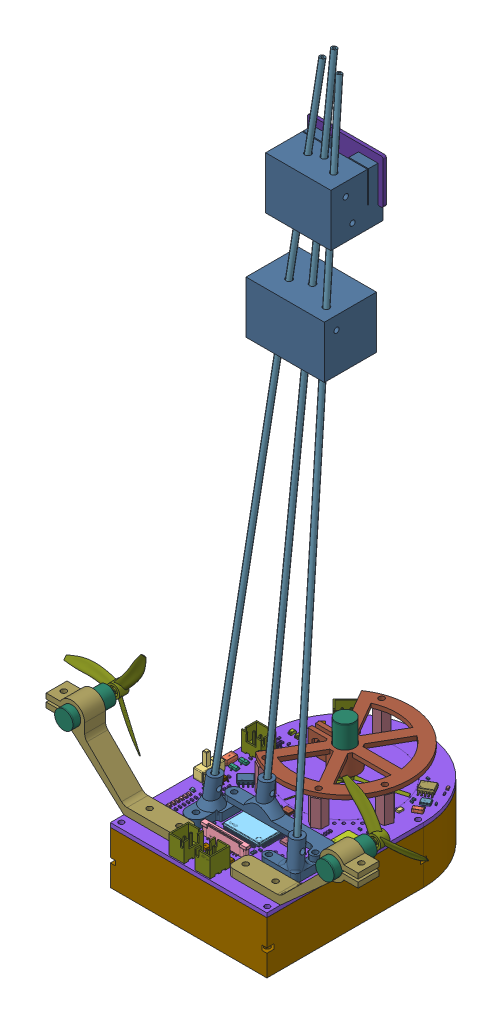
SolidWorks assembly full_assem, configuration Default. Lengths in mm.
Overall size (142.83 265.85 90).
339 component instances, 35 part files, 46 mates.
Components (placement in the parent):
- 3D_Main_v2_2024-07-05.step-1: 3D_Main_v2_2024-07-05.step [Default] at (-0.0126 0 0.0126) x (1 0 0) z (0 1 0) size (59.97 89.97 15.19)
  - a2ZF-C2.step-1: a2ZF-C2.step [Default] at (-11.43 -27.9401 1.5862) size (1 0.5 0.5)
    - C0402.step-1: C0402.step [Default] at origin size (1 0.5 0.5)
      - SOLID.step-1: SOLID.step [Default] at origin size (1 0.5 0.5)
  - a2ZF-C3.step-1: a2ZF-C3.step [Default] at (-2.286 -22.479 1.5862) x (0 -1 0) z (0 0 1) size (1 0.5 0.5)
    - C0402.step-1: C0402.step [Default] at origin size (1 0.5 0.5)
      - SOLID.step-1: SOLID.step [Default] at origin size (1 0.5 0.5)
  - a2ZF-C4.step-1: a2ZF-C4.step [Default] at (3.302 -22.479 1.5862) x (0 1 0) z (0 0 1) size (1 0.5 0.5)
    - C0402.step-1: C0402.step [Default] at origin size (1 0.5 0.5)
      - SOLID.step-1: SOLID.step [Default] at origin size (1 0.5 0.5)
  - a2ZF-C5.step-1: a2ZF-C5.step [Default] at (-4.445 -22.225 1.5862) x (0 -1 0) z (0 0 1) size (1 0.5 0.5)
    - C0402.step-1: C0402.step [Default] at origin size (1 0.5 0.5)
      - SOLID.step-1: SOLID.step [Default] at origin size (1 0.5 0.5)
  - a2ZF-C6.step-1: a2ZF-C6.step [Default] at (8.255 -40.6401 1.5862) x (-1 0 0) z (0 0 1) size (1 0.5 0.5)
    - C0402.step-1: C0402.step [Default] at origin size (1 0.5 0.5)
      - SOLID.step-1: SOLID.step [Default] at origin size (1 0.5 0.5)
  - a2ZF-C7.step-1: a2ZF-C7.step [Default] at (27.3051 -27.9401 1.5862) x (0 1 0) z (0 0 1) size (1 0.5 0.5)
    - C0402.step-1: C0402.step [Default] at origin size (1 0.5 0.5)
      - SOLID.step-1: SOLID.step [Default] at origin size (1 0.5 0.5)
  - a2ZF-C10.step-1: a2ZF-C10.step [Default] at (7.62 -43.1801 1.5862) size (1 0.5 0.5)
    - C0402.step-1: C0402.step [Default] at origin size (1 0.5 0.5)
      - SOLID.step-1: SOLID.step [Default] at origin size (1 0.5 0.5)
  - a2ZF-C9.step-1: a2ZF-C9.step [Default] at (7.62 -42.1641 1.5862) size (1 0.5 0.5)
    - C0402.step-1: C0402.step [Default] at origin size (1 0.5 0.5)
      - SOLID.step-1: SOLID.step [Default] at origin size (1 0.5 0.5)
  - a2ZF-C11.step-1: a2ZF-C11.step [Default] at (-17.78 -31.7501 1.5862) x (0 1 0) z (0 0 1) size (1 0.5 0.5)
    - C0402.step-1: C0402.step [Default] at origin size (1 0.5 0.5)
      - SOLID.step-1: SOLID.step [Default] at origin size (1 0.5 0.5)
  - a2ZF-C37.step-1: a2ZF-C37.step [Default] at (-21.59 -27.3051 1.5862) x (-1 0 0) z (0 0 1) size (1 0.5 0.5)
    - C0402.step-1: C0402.step [Default] at origin size (1 0.5 0.5)
      - SOLID.step-1: SOLID.step [Default] at origin size (1 0.5 0.5)
  - a2ZF-C12.step-1: a2ZF-C12.step [Default] at (20.32 -14.605 1.5862) x (-1 0 0) z (0 0 1) size (1 0.5 0.5)
    - C0402.step-1: C0402.step [Default] at origin size (1 0.5 0.5)
      - SOLID.step-1: SOLID.step [Default] at origin size (1 0.5 0.5)
  - a2ZF-C14.step-1: a2ZF-C14.step [Default] at (14.605 -25.4001 1.5862) size (1 0.5 0.5)
    - C0402.step-1: C0402.step [Default] at origin size (1 0.5 0.5)
      - SOLID.step-1: SOLID.step [Default] at origin size (1 0.5 0.5)
  - a2ZF-C15.step-1: a2ZF-C15.step [Default] at (24.892 -29.2101 1.5862) x (0 1 0) z (0 0 1) size (1 0.5 0.5)
    - C0402.step-1: C0402.step [Default] at origin size (1 0.5 0.5)
      - SOLID.step-1: SOLID.step [Default] at origin size (1 0.5 0.5)
  - a2ZF-C17.step-1: a2ZF-C17.step [Default] at (19.304 -29.2101 1.5862) x (0 -1 0) z (0 0 1) size (1 0.5 0.5)
    - C0402.step-1: C0402.step [Default] at origin size (1 0.5 0.5)
      - SOLID.step-1: SOLID.step [Default] at origin size (1 0.5 0.5)
  - a2ZF-C19.step-1: a2ZF-C19.step [Default] at (27.3051 -16.51 1.5862) x (0 -1 0) z (0 0 1) size (1 0.5 0.5)
    - C0402.step-1: C0402.step [Default] at origin size (1 0.5 0.5)
      - SOLID.step-1: SOLID.step [Default] at origin size (1 0.5 0.5)
  - a2ZF-C21.step-1: a2ZF-C21.step [Default] at (21.082 4.445 1.5862) x (-1 0 0) z (0 0 1) size (1 0.5 0.5)
    - C0402.step-1: C0402.step [Default] at origin size (1 0.5 0.5)
      - SOLID.step-1: SOLID.step [Default] at origin size (1 0.5 0.5)
  - a2ZF-C22.step-1: a2ZF-C22.step [Default] at (20.701 5.715 1.5862) size (1 0.5 0.5)
    - C0402.step-1: C0402.step [Default] at origin size (1 0.5 0.5)
      - SOLID.step-1: SOLID.step [Default] at origin size (1 0.5 0.5)
  - a2ZF-C23.step-1: a2ZF-C23.step [Default] at (16.51 15.24 1.5862) x (-1 0 0) z (0 0 1) size (1 0.5 0.5)
    - C0402.step-1: C0402.step [Default] at origin size (1 0.5 0.5)
      - SOLID.step-1: SOLID.step [Default] at origin size (1 0.5 0.5)
  - a2ZF-C24.step-1: a2ZF-C24.step [Default] at (-5.715 -50.8001 1.5862) x (-1 0 0) z (0 0 1) size (1 0.5 0.5)
    - C0402.step-1: C0402.step [Default] at origin size (1 0.5 0.5)
      - SOLID.step-1: SOLID.step [Default] at origin size (1 0.5 0.5)
  - a2ZF-C25.step-1: a2ZF-C25.step [Default] at (-5.715 -49.5301 1.5862) x (-1 0 0) z (0 0 1) size (1 0.5 0.5)
    - C0402.step-1: C0402.step [Default] at origin size (1 0.5 0.5)
      - SOLID.step-1: SOLID.step [Default] at origin size (1 0.5 0.5)
  - a2ZF-C26.step-1: a2ZF-C26.step [Default] at (25.2731 4.699 1.5862) x (0.866025 0.5 0) z (0 0 1) size (1 0.5 0.5)
    - C0402.step-1: C0402.step [Default] at origin size (1 0.5 0.5)
      - SOLID.step-1: SOLID.step [Default] at origin size (1 0.5 0.5)
  - a2ZF-C27.step-1: a2ZF-C27.step [Default] at (26.5431 8.382 1.5862) x (-0.5 0.866025 0) z (0 0 1) size (1 0.5 0.5)
    - C0402.step-1: C0402.step [Default] at origin size (1 0.5 0.5)
      - SOLID.step-1: SOLID.step [Default] at origin size (1 0.5 0.5)
  - a2ZF-C28.step-1: a2ZF-C28.step [Default] at (3.175 -50.8001 1.5862) x (-1 0 0) z (0 0 1) size (1 0.5 0.5)
    - C0402.step-1: C0402.step [Default] at origin size (1 0.5 0.5)
      - SOLID.step-1: SOLID.step [Default] at origin size (1 0.5 0.5)
  - a2ZF-C29.step-1: a2ZF-C29.step [Default] at (3.175 -49.5301 1.5862) x (-1 0 0) z (0 0 1) size (1 0.5 0.5)
    - C0402.step-1: C0402.step [Default] at origin size (1 0.5 0.5)
      - SOLID.step-1: SOLID.step [Default] at origin size (1 0.5 0.5)
  - a2ZF-C30.step-1: a2ZF-C30.step [Default] at (-19.05 11.43 1.5862) x (0.707107 -0.707107 0) z (0 0 1) size (1 0.5 0.5)
    - C0402.step-1: C0402.step [Default] at origin size (1 0.5 0.5)
      - SOLID.step-1: SOLID.step [Default] at origin size (1 0.5 0.5)
  - a2ZF-C31.step-1: a2ZF-C31.step [Default] at (-20.32 10.16 1.5862) x (0.707107 -0.707107 0) z (0 0 1) size (1 0.5 0.5)
    - C0402.step-1: C0402.step [Default] at origin size (1 0.5 0.5)
      - SOLID.step-1: SOLID.step [Default] at origin size (1 0.5 0.5)
  - a2ZF-C32.step-1: a2ZF-C32.step [Default] at (-13.462 -18.034 1.5862) x (0.707107 0.707107 0) z (0 0 1) size (1 0.5 0.5)
    - C0402.step-1: C0402.step [Default] at origin size (1 0.5 0.5)
      - SOLID.step-1: SOLID.step [Default] at origin size (1 0.5 0.5)
  - a2ZF-C33.step-1: a2ZF-C33.step [Default] at (10.16 -26.6701 1.5862) x (0 -1 0) z (0 0 1) size (1 0.5 0.5)
    - C0402.step-1: C0402.step [Default] at origin size (1 0.5 0.5)
      - SOLID.step-1: SOLID.step [Default] at origin size (1 0.5 0.5)
  - a2ZF-C34.step-1: a2ZF-C34.step [Default] at (-15.24 -26.6701 1.5862) x (-1 0 0) z (0 0 1) size (1 0.5 0.5)
    - C0402.step-1: C0402.step [Default] at origin size (1 0.5 0.5)
      - SOLID.step-1: SOLID.step [Default] at origin size (1 0.5 0.5)
  - a2ZF-C35.step-1: a2ZF-C35.step [Default] at (-5.715 -22.225 1.5862) x (0 1 0) z (0 0 1) size (1 0.5 0.5)
    - C0402.step-1: C0402.step [Default] at origin size (1 0.5 0.5)
      - SOLID.step-1: SOLID.step [Default] at origin size (1 0.5 0.5)
  - a2ZF-C36.step-1: a2ZF-C36.step [Default] at (-18.415 -29.2101 1.5862) x (-1 0 0) z (0 0 1) size (1 0.5 0.5)
    - C0402.step-1: C0402.step [Default] at origin size (1 0.5 0.5)
      - SOLID.step-1: SOLID.step [Default] at origin size (1 0.5 0.5)
  - a2ZF-C8.step-1: a2ZF-C8.step [Default] at (5.08 -22.86 1.5862) x (0 1 0) z (0 0 1) size (1 0.5 0.5)
    - C0402.step-1: C0402.step [Default] at origin size (1 0.5 0.5)
      - SOLID.step-1: SOLID.step [Default] at origin size (1 0.5 0.5)
  - a2ZF-C38.step-1: a2ZF-C38.step [Default] at (-9.525 -43.1801 1.5862) x (0 1 0) z (0 0 1) size (1 0.5 0.5)
    - C0402.step-1: C0402.step [Default] at origin size (1 0.5 0.5)
      - SOLID.step-1: SOLID.step [Default] at origin size (1 0.5 0.5)
  - a2ZF-C1.step-1: a2ZF-C1.step [Default] at (-9.525 -40.6401 1.5862) x (0 1 0) z (0 0 1) size (1 0.5 0.5)
    - C0402.step-1: C0402.step [Default] at origin size (1 0.5 0.5)
      - SOLID.step-1: SOLID.step [Default] at origin size (1 0.5 0.5)
  - a2ZF-C20.step-1: a2ZF-C20.step [Default] at (25.4001 2.54 1.5862) x (-0.866025 -0.5 0) z (0 0 1) size (3.2 1.6 1.3)
    - C1206.step-1: C1206.step [Default] at origin size (3.2 1.6 1.3)
      - SOLID-0.step-1: SOLID-0.step [Default] at origin size (3.2 1.6 1.3)
  - a2ZF-L1.step-1: a2ZF-L1.step [Default] at (21.59 -0.635 1.5862) x (0 1 0) z (0 0 1) size (2 1.3 0.61)
    - L0805.step-1: L0805.step [Default] at origin size (2 1.3 0.61)
      - COMPOUND.step-1: COMPOUND.step [Default] at origin size (2 1.3 0.61)
  - a2ZF-LED8.step-1: a2ZF-LED8.step [Default] at (24.257 -11.43 1.5862) x (0 -1 0) z (0 0 1) size (1.62 0.82 0.56)
    - LED0603-RD-YELLOW.step-1: LED0603-RD-YELLOW.step [Default] at origin size (1.62 0.82 0.56)
      - COMPOUND-1.step-1: COMPOUND-1.step [Default] at origin size (1.62 0.82 0.56)
  - a2ZF-LED2.step-1: a2ZF-LED2.step [Default] at (-24.13 -35.5601 1.5862) size (1.62 0.82 0.56)
    - LED0603-RD-YELLOW.step-1: LED0603-RD-YELLOW.step [Default] at origin size (1.62 0.82 0.56)
      - COMPOUND-1.step-1: COMPOUND-1.step [Default] at origin size (1.62 0.82 0.56)
  - a2ZF-LED3.step-1: a2ZF-LED3.step [Default] at (-24.13 -37.0841 1.5862) size (1.62 0.82 0.56)
    - LED0603-RD-YELLOW.step-1: LED0603-RD-YELLOW.step [Default] at origin size (1.62 0.82 0.56)
      - COMPOUND-1.step-1: COMPOUND-1.step [Default] at origin size (1.62 0.82 0.56)
  - a2ZF-LED4.step-1: a2ZF-LED4.step [Default] at (-24.13 -38.6081 1.5862) size (1.62 0.82 0.56)
    - LED0603-RD-YELLOW.step-1: LED0603-RD-YELLOW.step [Default] at origin size (1.62 0.82 0.56)
      - COMPOUND-1.step-1: COMPOUND-1.step [Default] at origin size (1.62 0.82 0.56)
  - a2ZF-LED5.step-1: a2ZF-LED5.step [Default] at (-24.13 -40.1321 1.5862) size (1.62 0.82 0.56)
    - LED0603-RD-YELLOW.step-1: LED0603-RD-YELLOW.step [Default] at origin size (1.62 0.82 0.56)
      - COMPOUND-1.step-1: COMPOUND-1.step [Default] at origin size (1.62 0.82 0.56)
  - a2ZF-LED6.step-1: a2ZF-LED6.step [Default] at (-24.13 -41.6561 1.5862) size (1.62 0.82 0.56)
    - LED0603-RD-YELLOW.step-1: LED0603-RD-YELLOW.step [Default] at origin size (1.62 0.82 0.56)
      - COMPOUND-1.step-1: COMPOUND-1.step [Default] at origin size (1.62 0.82 0.56)
  - a2ZF-LED7.step-1: a2ZF-LED7.step [Default] at (-24.13 -43.1801 1.5862) size (1.62 0.82 0.56)
    - LED0603-RD-YELLOW.step-1: LED0603-RD-YELLOW.step [Default] at origin size (1.62 0.82 0.56)
      - COMPOUND-1.step-1: COMPOUND-1.step [Default] at origin size (1.62 0.82 0.56)
  - a2ZF-LED10.step-1: a2ZF-LED10.step [Default] at (23.495 15.875 1.5862) x (0.5 -0.866025 0) z (0 0 1) size (1.62 0.82 0.56)
    - LED0603-RD-YELLOW.step-1: LED0603-RD-YELLOW.step [Default] at origin size (1.62 0.82 0.56)
      - COMPOUND-1.step-1: COMPOUND-1.step [Default] at origin size (1.62 0.82 0.56)
  - a2ZF-LED9.step-1: a2ZF-LED9.step [Default] at (22.733 -11.43 1.5862) x (0 -1 0) z (0 0 1) size (1.62 0.82 0.56)
    - LED0603-RD-YELLOW.step-1: LED0603-RD-YELLOW.step [Default] at origin size (1.62 0.82 0.56)
      - COMPOUND-1.step-1: COMPOUND-1.step [Default] at origin size (1.62 0.82 0.56)
  - a2ZF-LED1.step-1: a2ZF-LED1.step [Default] at (-24.765 -33.6551 1.5862) size (1.62 0.81 0.81)
    - LED0603-R-RD_WHITE.step-1: LED0603-R-RD_WHITE.step [Default] at origin size (1.62 0.81 0.81)
      - COMPOUND-2.step-1: COMPOUND-2.step [Default] at origin size (1.62 0.81 0.81)
  - a2ZF-L2.step-1: a2ZF-L2.step [Default] at (-22.225 -29.8451 1.5862) size (3 3 1.52)
    - IND-SMD_L3.0-W3.0_FNR30XXS.step-1: IND-SMD_L3.0-W3.0_FNR30XXS.step [Default] at origin size (3 3 1.52)
      - SOLID-3.step-1: SOLID-3.step [Default] at origin size (3 3 1.52)
  - a2ZF-LED12.step-1: a2ZF-LED12.step [Default] at (-22.225 4.445 1.5862) x (0 1 0) z (0 0 1) size (2.02 1.26 1.01)
    - LED0805-R-RD.step-1: LED0805-R-RD.step [Default] at origin size (2.02 1.26 1.01)
      - COMPOUND-4.step-1: COMPOUND-4.step [Default] at origin size (2.02 1.26 1.01)
  - a2ZF-LED11.step-1: a2ZF-LED11.step [Default] at (-24.765 4.445 1.5862) x (0 1 0) z (0 0 1) size (2.02 1.26 1.01)
    - LED0805-R-RD.step-1: LED0805-R-RD.step [Default] at origin size (2.02 1.26 1.01)
      - COMPOUND-4.step-1: COMPOUND-4.step [Default] at origin size (2.02 1.26 1.01)
  - a2ZF-R2.step-1: a2ZF-R2.step [Default] at (-3.302 -22.479 1.5862) x (0 -1 0) z (0 0 1) size (1 0.5 0.5)
    - R0402.step-1: R0402.step [Default] at origin size (1 0.5 0.5)
      - SOLID-5.step-1: SOLID-5.step [Default] at origin size (1 0.5 0.5)
  - a2ZF-R3.step-1: a2ZF-R3.step [Default] at (-7.62 -43.1801 1.5862) size (1 0.5 0.5)
    - R0402.step-1: R0402.step [Default] at origin size (1 0.5 0.5)
      - SOLID-5.step-1: SOLID-5.step [Default] at origin size (1 0.5 0.5)
  - a2ZF-R4.step-1: a2ZF-R4.step [Default] at (-7.62 -48.2601 1.5862) size (1 0.5 0.5)
    - R0402.step-1: R0402.step [Default] at origin size (1 0.5 0.5)
      - SOLID-5.step-1: SOLID-5.step [Default] at origin size (1 0.5 0.5)
  - a2ZF-R5.step-1: a2ZF-R5.step [Default] at (-21.59 -33.6551 1.5862) size (1 0.5 0.5)
    - R0402.step-1: R0402.step [Default] at origin size (1 0.5 0.5)
      - SOLID-5.step-1: SOLID-5.step [Default] at origin size (1 0.5 0.5)
  - a2ZF-R13.step-1: a2ZF-R13.step [Default] at (26.0351 -29.2101 1.5862) x (0 1 0) z (0 0 1) size (1 0.5 0.5)
    - R0402.step-1: R0402.step [Default] at origin size (1 0.5 0.5)
      - SOLID-5.step-1: SOLID-5.step [Default] at origin size (1 0.5 0.5)
  - a2ZF-R12.step-1: a2ZF-R12.step [Default] at (15.24 -24.13 1.5862) x (-1 0 0) z (0 0 1) size (1 0.5 0.5)
    - R0402.step-1: R0402.step [Default] at origin size (1 0.5 0.5)
      - SOLID-5.step-1: SOLID-5.step [Default] at origin size (1 0.5 0.5)
  - a2ZF-R6.step-1: a2ZF-R6.step [Default] at (-21.59 -35.5601 1.5862) size (1 0.5 0.5)
    - R0402.step-1: R0402.step [Default] at origin size (1 0.5 0.5)
      - SOLID-5.step-1: SOLID-5.step [Default] at origin size (1 0.5 0.5)
  - a2ZF-R7.step-1: a2ZF-R7.step [Default] at (-21.59 -37.0841 1.5862) size (1 0.5 0.5)
    - R0402.step-1: R0402.step [Default] at origin size (1 0.5 0.5)
      - SOLID-5.step-1: SOLID-5.step [Default] at origin size (1 0.5 0.5)
  - a2ZF-R8.step-1: a2ZF-R8.step [Default] at (-21.59 -38.6081 1.5862) size (1 0.5 0.5)
    - R0402.step-1: R0402.step [Default] at origin size (1 0.5 0.5)
      - SOLID-5.step-1: SOLID-5.step [Default] at origin size (1 0.5 0.5)
  - a2ZF-R9.step-1: a2ZF-R9.step [Default] at (-21.59 -40.1321 1.5862) size (1 0.5 0.5)
    - R0402.step-1: R0402.step [Default] at origin size (1 0.5 0.5)
      - SOLID-5.step-1: SOLID-5.step [Default] at origin size (1 0.5 0.5)
  - a2ZF-R10.step-1: a2ZF-R10.step [Default] at (-21.59 -41.6561 1.5862) size (1 0.5 0.5)
    - R0402.step-1: R0402.step [Default] at origin size (1 0.5 0.5)
      - SOLID-5.step-1: SOLID-5.step [Default] at origin size (1 0.5 0.5)
  - a2ZF-R11.step-1: a2ZF-R11.step [Default] at (-21.59 -43.1801 1.5862) size (1 0.5 0.5)
    - R0402.step-1: R0402.step [Default] at origin size (1 0.5 0.5)
      - SOLID-5.step-1: SOLID-5.step [Default] at origin size (1 0.5 0.5)
  - a2ZF-R14.step-1: a2ZF-R14.step [Default] at (24.13 -13.97 1.5862) x (0 -1 0) z (0 0 1) size (1 0.5 0.5)
    - R0402.step-1: R0402.step [Default] at origin size (1 0.5 0.5)
      - SOLID-5.step-1: SOLID-5.step [Default] at origin size (1 0.5 0.5)
  - a2ZF-R15.step-1: a2ZF-R15.step [Default] at (22.86 -13.97 1.5862) x (0 -1 0) z (0 0 1) size (1 0.5 0.5)
    - R0402.step-1: R0402.step [Default] at origin size (1 0.5 0.5)
      - SOLID-5.step-1: SOLID-5.step [Default] at origin size (1 0.5 0.5)
  - a2ZF-R16.step-1: a2ZF-R16.step [Default] at (28.5751 -13.97 1.5862) x (0 1 0) z (0 0 1) size (1 0.5 0.5)
    - R0402.step-1: R0402.step [Default] at origin size (1 0.5 0.5)
      - SOLID-5.step-1: SOLID-5.step [Default] at origin size (1 0.5 0.5)
  - a2ZF-R17.step-1: a2ZF-R17.step [Default] at (27.3051 -13.97 1.5862) x (0 1 0) z (0 0 1) size (1 0.5 0.5)
    - R0402.step-1: R0402.step [Default] at origin size (1 0.5 0.5)
      - SOLID-5.step-1: SOLID-5.step [Default] at origin size (1 0.5 0.5)
  - a2ZF-R18.step-1: a2ZF-R18.step [Default] at (28.5751 -16.637 1.5862) x (0 1 0) z (0 0 1) size (1 0.5 0.5)
    - R0402.step-1: R0402.step [Default] at origin size (1 0.5 0.5)
      - SOLID-5.step-1: SOLID-5.step [Default] at origin size (1 0.5 0.5)
  - a2ZF-R19.step-1: a2ZF-R19.step [Default] at (15.24 -22.86 1.5862) x (-1 0 0) z (0 0 1) size (1 0.5 0.5)
    - R0402.step-1: R0402.step [Default] at origin size (1 0.5 0.5)
      - SOLID-5.step-1: SOLID-5.step [Default] at origin size (1 0.5 0.5)
  - a2ZF-R20.step-1: a2ZF-R20.step [Default] at (15.24 -21.844 1.5862) x (-1 0 0) z (0 0 1) size (1 0.5 0.5)
    - R0402.step-1: R0402.step [Default] at origin size (1 0.5 0.5)
      - SOLID-5.step-1: SOLID-5.step [Default] at origin size (1 0.5 0.5)
  - a2ZF-R21.step-1: a2ZF-R21.step [Default] at (15.24 -20.828 1.5862) x (-1 0 0) z (0 0 1) size (1 0.5 0.5)
    - R0402.step-1: R0402.step [Default] at origin size (1 0.5 0.5)
      - SOLID-5.step-1: SOLID-5.step [Default] at origin size (1 0.5 0.5)
  - a2ZF-R23.step-1: a2ZF-R23.step [Default] at (-19.05 -27.3051 1.5862) x (0 -1 0) z (0 0 1) size (1 0.5 0.5)
    - R0402.step-1: R0402.step [Default] at origin size (1 0.5 0.5)
      - SOLID-5.step-1: SOLID-5.step [Default] at origin size (1 0.5 0.5)
  - a2ZF-R24.step-1: a2ZF-R24.step [Default] at (-6.985 -20.32 1.5862) x (0 1 0) z (0 0 1) size (1 0.5 0.5)
    - R0402.step-1: R0402.step [Default] at origin size (1 0.5 0.5)
      - SOLID-5.step-1: SOLID-5.step [Default] at origin size (1 0.5 0.5)
  - a2ZF-R25.step-1: a2ZF-R25.step [Default] at (-19.05 -25.4001 1.5862) x (0 -1 0) z (0 0 1) size (1 0.5 0.5)
    - R0402.step-1: R0402.step [Default] at origin size (1 0.5 0.5)
      - SOLID-5.step-1: SOLID-5.step [Default] at origin size (1 0.5 0.5)
  - a2ZF-R26.step-1: a2ZF-R26.step [Default] at (-6.985 -22.225 1.5862) x (0 1 0) z (0 0 1) size (1 0.5 0.5)
    - R0402.step-1: R0402.step [Default] at origin size (1 0.5 0.5)
      - SOLID-5.step-1: SOLID-5.step [Default] at origin size (1 0.5 0.5)
  - a2ZF-R27.step-1: a2ZF-R27.step [Default] at (-22.225 -22.225 1.5862) size (1 0.5 0.5)
    - R0402.step-1: R0402.step [Default] at origin size (1 0.5 0.5)
      - SOLID-5.step-1: SOLID-5.step [Default] at origin size (1 0.5 0.5)
  - a2ZF-R28.step-1: a2ZF-R28.step [Default] at (-25.4001 0 1.5862) x (0 1 0) z (0 0 1) size (1 0.5 0.5)
    - R0402.step-1: R0402.step [Default] at origin size (1 0.5 0.5)
      - SOLID-5.step-1: SOLID-5.step [Default] at origin size (1 0.5 0.5)
  - a2ZF-R29.step-1: a2ZF-R29.step [Default] at (-23.495 -0.635 1.5862) x (-1 0 0) z (0 0 1) size (1 0.5 0.5)
    - R0402.step-1: R0402.step [Default] at origin size (1 0.5 0.5)
      - SOLID-5.step-1: SOLID-5.step [Default] at origin size (1 0.5 0.5)
  - a2ZF-R31.step-1: a2ZF-R31.step [Default] at (-21.59 0 1.5862) x (0 1 0) z (0 0 1) size (1 0.5 0.5)
    - R0402.step-1: R0402.step [Default] at origin size (1 0.5 0.5)
      - SOLID-5.step-1: SOLID-5.step [Default] at origin size (1 0.5 0.5)
  - a2ZF-R22.step-1: a2ZF-R22.step [Default] at (24.765 13.335 1.5862) x (0.5 -0.866025 0) z (0 0 1) size (1 0.5 0.5)
    - R0402.step-1: R0402.step [Default] at origin size (1 0.5 0.5)
      - SOLID-5.step-1: SOLID-5.step [Default] at origin size (1 0.5 0.5)
  - a2ZF-R30.step-1: a2ZF-R30.step [Default] at (-24.13 -12.065 1.5862) x (-1 0 0) z (0 0 1) size (1 0.5 0.5)
    - R0402.step-1: R0402.step [Default] at origin size (1 0.5 0.5)
      - SOLID-5.step-1: SOLID-5.step [Default] at origin size (1 0.5 0.5)
  - a2ZF-R1.step-1: a2ZF-R1.step [Default] at (10.16 -29.2101 1.5862) size (1 0.5 0.5)
    - R0402.step-1: R0402.step [Default] at origin size (1 0.5 0.5)
      - SOLID-5.step-1: SOLID-5.step [Default] at origin size (1 0.5 0.5)
  - a2ZF-U5.step-1: a2ZF-U5.step [Default] at (5.715 -50.1651 1.5862) x (0 1 0) z (0 0 1) size (2.02 2 0.81)
    - WSON-8_L2.0-W2.0-P0.50-TL-EP.step-1: WSON-8_L2.0-W2.0-P0.50-TL-EP.step [Default] at origin size (2.02 2 0.81)
      - COMPOUND-6.step-1: COMPOUND-6.step [Default] at origin size (2.02 2 0.81)
  - a2ZF-U6.step-1: a2ZF-U6.step [Default] at (-21.59 12.7 1.5862) x (-0.707107 -0.707107 0) z (0 0 1) size (2.02 2 0.81)
    - WSON-8_L2.0-W2.0-P0.50-TL-EP.step-1: WSON-8_L2.0-W2.0-P0.50-TL-EP.step [Default] at origin size (2.02 2 0.81)
      - COMPOUND-6.step-1: COMPOUND-6.step [Default] at origin size (2.02 2 0.81)
  - a2ZF-U4.step-1: a2ZF-U4.step [Default] at (-3.175 -50.1651 1.5862) x (0 1 0) z (0 0 1) size (2.02 2 0.81)
    - WSON-8_L2.0-W2.0-P0.50-TL-EP.step-1: WSON-8_L2.0-W2.0-P0.50-TL-EP.step [Default] at origin size (2.02 2 0.81)
      - COMPOUND-6.step-1: COMPOUND-6.step [Default] at origin size (2.02 2 0.81)
  - a2ZF-U7.step-1: a2ZF-U7.step [Default] at (-17.78 -20.32 1.5862) x (-0.707107 -0.707107 0) z (0 0 1) size (4.9 6 1.5)
    - SOP-8_L4.9-W3.9-P1.27-LS6.0-BL.step-1: SOP-8_L4.9-W3.9-P1.27-LS6.0-BL.step [Default] at origin size (4.9 6 1.5)
      - COMPOUND-7.step-1: COMPOUND-7.step [Default] at origin size (4.9 6 1.5)
  - a2ZF-X2.step-1: a2ZF-X2.step [Default] at (22.098 -29.2101 1.5862) size (3.2 2.5 0.81)
    - OSC-SMD_4P-L3.2-W2.5-BL.step-1: OSC-SMD_4P-L3.2-W2.5-BL.step [Default] at origin size (3.2 2.5 0.81)
      - SOLID-8.step-1: SOLID-8.step [Default] at origin size (3.2 2.5 0.81)
  - a2ZF-X1.step-1: a2ZF-X1.step [Default] at (0.508 -22.479 1.5862) x (-1 0 0) z (0 0 1) size (3.2 2.5 0.81)
    - OSC-SMD_4P-L3.2-W2.5-BL.step-1: OSC-SMD_4P-L3.2-W2.5-BL.step [Default] at origin size (3.2 2.5 0.81)
      - SOLID-8.step-1: SOLID-8.step [Default] at origin size (3.2 2.5 0.81)
  - a2ZF-U3.step-1: a2ZF-U3.step [Default] at (20.193 11.43 1.5862) x (0.866025 0.5 0) z (0 0 1) size (5 6 1.8)
    - SSOP-10_L5.0-W3.9-P1.00-LS6.0-BL-EP.step-1: SSOP-10_L5.0-W3.9-P1.00-LS6.0-BL-EP.step [Default] at origin size (5 6 1.8)
      - COMPOUND-9.step-1: COMPOUND-9.step [Default] at origin size (5 6 1.8)
  - a2ZF-U8.step-1: a2ZF-U8.step [Default] at (10.795 -33.0201 1.5862) size (3 2.5 0.92)
    - LGA-14_L3.0-W2.5-P0.50-TL.step-1: LGA-14_L3.0-W2.5-P0.50-TL.step [Default] at origin size (3 2.5 0.92)
      - COMPOUND-10.step-1: COMPOUND-10.step [Default] at origin size (3 2.5 0.92)
  - a2ZF-X3.step-1: a2ZF-X3.step [Default] at (24.003 6.985 1.5862) x (0.866025 0.5 0) z (0 0 1) size (3.2 2.5 0.81)
    - CRYSTAL-SMD_4P-L3.2-W2.5-BL.step-1: CRYSTAL-SMD_4P-L3.2-W2.5-BL.step [Default] at origin size (3.2 2.5 0.81)
      - SOLID-11.step-1: SOLID-11.step [Default] at origin size (3.2 2.5 0.81)
  - a2ZF-CN2.step-1: a2ZF-CN2.step [Default] at (17.78 -31.7501 0) x (0 1 0) z (0 0 -1) size (8 3.2 6.9)
    - CONN-TH_5P-P1.25_HCTL_HC-1.25-5A.step-1: CONN-TH_5P-P1.25_HCTL_HC-1.25-5A.step [Default] at origin size (8 3.2 6.9)
      - COMPOUND-12.step-1: COMPOUND-12.step [Default] at origin size (8 3.2 6.9)
  - a2ZF-CN6.step-1: a2ZF-CN6.step [Default] at (-17.145 -14.605 1.5862) x (-0.707107 0.707107 0) z (0 0 1) size (8 3.2 6.9)
    - CONN-TH_5P-P1.25_HCTL_HC-1.25-5A.step-1: CONN-TH_5P-P1.25_HCTL_HC-1.25-5A.step [Default] at origin size (8 3.2 6.9)
      - COMPOUND-12.step-1: COMPOUND-12.step [Default] at origin size (8 3.2 6.9)
  - a2ZF-CN1.step-1: a2ZF-CN1.step [Default] at (13.97 -31.7501 0) x (0 1 0) z (0 0 -1) size (8 3.2 6.9)
    - CONN-TH_5P-P1.25_HCTL_HC-1.25-5A.step-1: CONN-TH_5P-P1.25_HCTL_HC-1.25-5A.step [Default] at origin size (8 3.2 6.9)
      - COMPOUND-12.step-1: COMPOUND-12.step [Default] at origin size (8 3.2 6.9)
  - a2ZF-CN4.step-1: a2ZF-CN4.step [Default] at (4.445 -55.8801 1.5862) x (0 1 0) z (0 0 1) size (7.5 5.9 10.6)
    - CONN-TH_2P-P2.50_HX25003-2A.step-1: CONN-TH_2P-P2.50_HX25003-2A.step [Default] at origin size (7.5 5.9 10.6)
      - COMPOUND-13.step-1: COMPOUND-13.step [Default] at origin size (7.5 5.9 10.6)
  - a2ZF-CN5.step-1: a2ZF-CN5.step [Default] at (-15.875 16.51 1.5862) x (-0.707107 -0.707107 0) z (0 0 1) size (7.5 5.9 10.6)
    - CONN-TH_2P-P2.50_HX25003-2A.step-1: CONN-TH_2P-P2.50_HX25003-2A.step [Default] at origin size (7.5 5.9 10.6)
      - COMPOUND-13.step-1: COMPOUND-13.step [Default] at origin size (7.5 5.9 10.6)
  - a2ZF-CN7.step-1: a2ZF-CN7.step [Default] at (-24.765 -8.89 1.5862) x (-1 0 0) z (0 0 1) size (7.5 5.9 10.6)
    - CONN-TH_2P-P2.50_HX25003-2A.step-1: CONN-TH_2P-P2.50_HX25003-2A.step [Default] at origin size (7.5 5.9 10.6)
      - COMPOUND-13.step-1: COMPOUND-13.step [Default] at origin size (7.5 5.9 10.6)
  - a2ZF-CN3.step-1: a2ZF-CN3.step [Default] at (-4.445 -55.8801 1.5862) x (0 -1 0) z (0 0 1) size (7.5 5.9 10.6)
    - CONN-TH_2P-P2.50_HX25003-2A.step-1: CONN-TH_2P-P2.50_HX25003-2A.step [Default] at origin size (7.5 5.9 10.6)
      - COMPOUND-13.step-1: COMPOUND-13.step [Default] at origin size (7.5 5.9 10.6)
  - a2ZF-U11.step-1: a2ZF-U11.step [Default] at (-23.495 -3.175 1.5862) x (-1 0 0) z (0 0 1) size (2.81 2.9 1.65)
    - SOT-23-6_L2.9-W1.6-P0.95-LS2.8-BR.step-1: SOT-23-6_L2.9-W1.6-P0.95-LS2.8-BR.step [Default] at origin size (2.81 2.9 1.65)
      - COMPOUND-14.step-1: COMPOUND-14.step [Default] at origin size (2.81 2.9 1.65)
  - a2ZF-U10.step-1: a2ZF-U10.step [Default] at (-22.225 -24.765 1.5862) x (-1 0 0) z (0 0 1) size (2.89 2.78 1.2)
    - SOT-23-5_L3.0-W1.7-P0.95-LS2.8-BR.step-1: SOT-23-5_L3.0-W1.7-P0.95-LS2.8-BR.step [Default] at origin size (2.89 2.78 1.2)
      - COMPOUND-15.step-1: COMPOUND-15.step [Default] at origin size (2.89 2.78 1.2)
  - a2ZF-U9.step-1: a2ZF-U9.step [Default] at (-15.24 -29.2101 1.5862) size (2.9 3.01 1.25)
    - SOT-23-5_L3.0-W1.7-P0.95-LS2.8-BL.step-1: SOT-23-5_L3.0-W1.7-P0.95-LS2.8-BL.step [Default] at origin size (2.9 3.01 1.25)
      - COMPOUND-16.step-1: COMPOUND-16.step [Default] at origin size (2.9 3.01 1.25)
  - a2ZF-D1.step-1: a2ZF-D1.step [Default] at (-27.3051 -17.145 1.5862) x (0 -1 0) z (0 0 1) size (4.7 2.6 2.1)
    - SMA_L4.3-W2.6-LS5.2-RD.step-1: SMA_L4.3-W2.6-LS5.2-RD.step [Default] at origin size (4.7 2.6 2.1)
      - COMPOUND-17.step-1: COMPOUND-17.step [Default] at origin size (4.7 2.6 2.1)
  - a2ZF-SW1.step-1: a2ZF-SW1.step [Default] at (-26.6701 -25.4001 1.5862) x (0 1 0) z (0 0 1) size (8.71 3.71 13.3)
    - SW-TH_KH-SS12D01-G3-5.0.step-1: SW-TH_KH-SS12D01-G3-5.0.step [Default] at origin size (8.71 3.71 13.3)
      - COMPOUND-18.step-1: COMPOUND-18.step [Default] at origin size (8.71 3.71 13.3)
  - a2ZF-FPC2.step-1: a2ZF-FPC2.step [Default] at (0 -45.7201 1.5862) size (17.6 3 4.4)
    - CONN-SMD-24_AFC11-S24ICA-00.step-1: CONN-SMD-24_AFC11-S24ICA-00.step [Default] at origin size (17.6 3 4.4)
      - COMPOUND-19.step-1: COMPOUND-19.step [Default] at origin size (17.6 3 4.4)
  - a2ZF-U1.step-1: a2ZF-U1.step [Default] at (0 -33.0201 1.5862) x (-1 0 0) z (0 0 1) size (16 16 1.5)
    - LQFP-100_L14.0-W14.0-P0.50-LS16.0-BL.step-1: LQFP-100_L14.0-W14.0-P0.50-LS16.0-BL.step [Default] at origin size (16 16 1.5)
      - SOLID-20.step-1: SOLID-20.step [Default] at origin size (16 16 1.5)
  - a2ZF-Q2.step-1: a2ZF-Q2.step [Default] at (-24.13 -14.6728 1.5862) x (0 1 0) z (0 0 1) size (2.51 2.9 1.05)
    - SOT-23_L2.9-W1.3-P1.90-LS2.4-BR.step-1: SOT-23_L2.9-W1.3-P1.90-LS2.4-BR.step [Default] at origin size (2.51 2.9 1.05)
      - COMPOUND-21.step-1: COMPOUND-21.step [Default] at origin size (2.51 2.9 1.05)
  - a2ZF-Q1.step-1: a2ZF-Q1.step [Default] at (-24.13 -18.4828 1.5862) x (0 1 0) z (0 0 1) size (2.51 2.9 1.05)
    - SOT-23_L2.9-W1.3-P1.90-LS2.4-BR.step-1: SOT-23_L2.9-W1.3-P1.90-LS2.4-BR.step [Default] at origin size (2.51 2.9 1.05)
      - COMPOUND-21.step-1: COMPOUND-21.step [Default] at origin size (2.51 2.9 1.05)
  - a2ZF-U2.step-1: a2ZF-U2.step [Default] at (22.86 -21.59 1.5862) size (9 9 1.45)
    - LQFP-48_L7.0-W7.0-P0.50-LS9.0-BL.step-1: LQFP-48_L7.0-W7.0-P0.50-LS9.0-BL.step [Default] at origin size (9 9 1.45)
      - COMPOUND-22.step-1: COMPOUND-22.step [Default] at origin size (9 9 1.45)
  - Board.step-1: Board.step [Default] at origin size (59.97 89.97 1.59)
- base-1: base [Default] at origin size (60 20 90)
- CameraBase-1: CameraBase [Default] at (-0.0126 1.5862 -2.0203) size (43.72 210 48.71)
- FanHolder-1: FanHolder [Default] at (-0.0127 -4.8138 0.0125) size (38.77 8 49.44)
- PropHolder1-1: PropHolder1 [Default] at (18.4024 1.5862 50.8127) x (-1 0 0) z (0 0 -1) size (50.07 28 8)
- PropHolder1-2: PropHolder1 [Default] at (-18.4277 1.5862 50.8127) size (50.07 28 8)
- support_10mm-1: support_10mm [Default] at (10.1473 1.5862 20.3325) x (0.841363 0 0.54047) z (-0.54047 0 0.841363) size (5.77 10 5)
- support_10mm-2: support_10mm [Default] at (21.5773 1.5862 6.3625) x (0.979462 0 -0.201628) z (0.201628 0 0.979462) size (5.77 10 5)
- support_10mm-3: support_10mm [Default] at (-7.6327 1.5862 -21.5775) x (0.962278 0 -0.272067) z (0.272067 0 0.962278) size (5.77 10 5)
- support_10mm-4: support_10mm [Default] at (-10.1727 1.5862 20.3326) x (0.888193 0 0.459471) z (-0.459471 0 0.888193) size (5.77 10 5)
- CF_stick_2x1x240-1: CF_stick_2x1x240 [Default] at (-8.394 123.3985 21.8058) x (0.99891 -0.046572 0.003098) z (0.003098 0.13239 0.991193) size (2 240 2)
- CF_stick_2x1x240-2: CF_stick_2x1x240 [Default] at (14.1701 122.8886 24.8475) x (-0.144235 0.135924 0.980164) z (-0.986445 -0.098072 -0.13156) size (2 240 2)
- CF_stick_2x1x240-3: CF_stick_2x1x240 [Default] at (-0.0126 126.4699 17.5243) x (-0.077129 0.11059 0.990869) z (-0.997021 -0.008555 -0.076653) size (2 240 2)
- 716_1mm-1: 716_1mm [Default] at (49.9874 24.5862 57.3127) x (1 0 0) z (0 1 0) size (7 21.5 7)
- 716_1mm-2: 716_1mm [Default] at (-50.0127 24.5862 57.3127) x (-0.923728 -0.383049 0) z (0.383049 -0.923728 0) size (7 21.5 7)
- 716_1mm-3: 716_1mm [Default] at (-0.0127 21.1862 0.0125) x (-0.837169 0 -0.546944) z (-0.546944 0 0.837169) size (7 21.5 7)
- propeller_1608-1: propeller_1608 [Default] at (-0.0127 -0.8138 0.0125) x (0.955285 0 0.295685) z (-0.295685 0 0.955285) size (34.5 3.6 31.33)
- propeller_1608-2: propeller_1608 [Default] at (49.9874 24.5862 35.3127) x (-0.821939 -0.569576 0) z (-0.569576 0.821939 0) size (34.5 3.6 31.33)
- propeller_1608-3: propeller_1608 [Default] at (-50.0127 24.5862 35.3127) x (0.923728 0.383049 0) z (0.383049 -0.923728 0) size (34.5 3.6 31.33)
- CameraClip_0mm-1: CameraClip_0mm [Default] at (0 211.5862 -1.2703) size (29 17 1.2)
Mates (geometry in assembly coordinates):
- Coincident2: coincident anti-aligned: plane of 3D_Main_v2_2024-07-05.step-1/Board.step-1 through (-0.0126 0 20.9034) normal (0 -1 0)
- Distance1: distance = 60 mm aligned: plane of 3D_Main_v2_2024-07-05.step-1/Board.step-1 through (29.9747 0 60) normal (0 0 1)
- Distance2: distance = 30 mm anti-aligned: plane of 3D_Main_v2_2024-07-05.step-1/Board.step-1 through (-30 0 60) normal (-1 0 0)
- Coincident7: coincident anti-aligned: plane of 3D_Main_v2_2024-07-05.step-1/Board.step-1 through (-0.0126 0 20.9034) normal (0 -1 0); plane of base-1 through (0 0 0) normal (0 1 0)
- Coincident8: coincident aligned: plane of 3D_Main_v2_2024-07-05.step-1/Board.step-1 through (29.9747 0 60) normal (0 0 1); plane of base-1 through (0 -20 60) normal (0 0 1)
- Coincident9: coincident aligned: plane of 3D_Main_v2_2024-07-05.step-1/Board.step-1 through (-30 0 60) normal (-1 0 0); plane of base-1 through (-30 -20 0) normal (-1 0 0)
- Coincident10: coincident anti-aligned: plane of 3D_Main_v2_2024-07-05.step-1/Board.step-1 through (-0.0126 1.5862 20.9034) normal (0 1 0); plane of CameraBase-1 through (-14.4826 1.5862 31.8977) normal (0 -1 0)
- Concentric1: concentric anti-aligned: cylinder of 3D_Main_v2_2024-07-05.step-1/Board.step-1 through (-13.9827 0 43.1927) axis (0 -1 0) radius 1; cylinder of CameraBase-1 through (-13.9826 1.5861 43.1927) axis (0 1 0) radius 1.05
- Concentric2: concentric anti-aligned: cylinder of 3D_Main_v2_2024-07-05.step-1/Board.step-1 through (13.9574 0 43.1927) axis (0 -1 0) radius 1; cylinder of CameraBase-1 through (13.9574 1.5861 43.1927) axis (0 1 0) radius 1.05
- Coincident11: coincident anti-aligned: plane of FanHolder-1 through (-0.0127 11.5862 0.0125) normal (0 -1 0); plane of support_10mm-4 through (-10.1727 11.5862 20.3326) normal (0 1 0)
- Coincident12: coincident anti-aligned: plane of FanHolder-1 through (-0.0127 11.5862 0.0125) normal (0 -1 0); plane of support_10mm-2 through (21.5773 11.5862 6.3625) normal (0 1 0)
- Coincident13: coincident anti-aligned: plane of FanHolder-1 through (-0.0127 11.5862 0.0125) normal (0 -1 0); plane of support_10mm-3 through (-7.6327 11.5862 -21.5775) normal (0 1 0)
- Coincident14: coincident anti-aligned: plane of FanHolder-1 through (-0.0127 11.5862 0.0125) normal (0 -1 0); plane of support_10mm-1 through (10.1473 11.5862 20.3325) normal (0 1 0)
- Concentric3: concentric anti-aligned: cylinder of FanHolder-1 through (-7.6327 5.1862 -21.5775) axis (0 1 0) radius 1.05; cylinder of support_10mm-3 through (-7.6327 11.5862 -21.5775) axis (0 -1 0) radius 1.15
- Concentric4: concentric anti-aligned: cylinder of FanHolder-1 through (21.5773 5.1862 6.3625) axis (0 1 0) radius 1.05; cylinder of support_10mm-2 through (21.5773 11.5862 6.3625) axis (0 -1 0) radius 1.15
- Concentric5: concentric anti-aligned: cylinder of FanHolder-1 through (10.1473 5.1862 20.3325) axis (0 1 0) radius 1.05; cylinder of support_10mm-1 through (10.1473 11.5862 20.3325) axis (0 -1 0) radius 1.15
- Concentric6: concentric anti-aligned: cylinder of FanHolder-1 through (-10.1727 5.1862 20.3325) axis (0 1 0) radius 1.05; cylinder of support_10mm-4 through (-10.1727 11.5862 20.3326) axis (0 -1 0) radius 1.15
- Coincident15: coincident anti-aligned: plane of 3D_Main_v2_2024-07-05.step-1/Board.step-1 through (-0.0126 1.5862 20.9034) normal (0 1 0); plane of support_10mm-1 through (10.1473 1.5862 20.3325) normal (0 -1 0)
- Concentric7: concentric aligned: cylinder of support_10mm-3 through (-7.6327 11.5862 -21.5775) axis (0 -1 0) radius 1.15; cylinder of 3D_Main_v2_2024-07-05.step-1/Board.step-1 through (-7.6327 0 -21.5775) axis (0 -1 0) radius 1
- Concentric8: concentric aligned: cylinder of 3D_Main_v2_2024-07-05.step-1/Board.step-1 through (-10.1727 0 20.3326) axis (0 -1 0) radius 1; cylinder of support_10mm-4 through (-10.1727 11.5862 20.3326) axis (0 -1 0) radius 1.15
- Coincident18: coincident anti-aligned: plane of 3D_Main_v2_2024-07-05.step-1/Board.step-1 through (-0.0126 1.5862 20.9034) normal (0 1 0); plane of PropHolder1-2 through (-18.4277 1.5862 50.8127) normal (0 -1 0)
- Coincident19: coincident anti-aligned: plane of 3D_Main_v2_2024-07-05.step-1/Board.step-1 through (-0.0126 1.5862 20.9034) normal (0 1 0); plane of PropHolder1-1 through (18.4024 1.5862 50.8127) normal (0 -1 0)
- Concentric9: concentric aligned: cylinder of 3D_Main_v2_2024-07-05.step-1/Board.step-1 through (12.6874 0 50.8127) axis (0 -1 0) radius 1; cylinder of PropHolder1-1 through (12.6874 4.5862 50.8127) axis (0 -1 0) radius 1.05
- Concentric10: concentric aligned: cylinder of 3D_Main_v2_2024-07-05.step-1/Board.step-1 through (24.1174 0 50.8127) axis (0 -1 0) radius 1; cylinder of PropHolder1-1 through (24.1174 4.5862 50.8127) axis (0 -1 0) radius 1.05
- Concentric11: concentric aligned: cylinder of 3D_Main_v2_2024-07-05.step-1/Board.step-1 through (-24.1427 0 50.8127) axis (0 -1 0) radius 1; cylinder of PropHolder1-2 through (-24.1427 4.5862 50.8127) axis (0 -1 0) radius 1.05
- Concentric12: concentric aligned: cylinder of 3D_Main_v2_2024-07-05.step-1/Board.step-1 through (-12.7127 0 50.8127) axis (0 -1 0) radius 1; cylinder of PropHolder1-2 through (-12.7127 4.5862 50.8127) axis (0 -1 0) radius 1.05
- Coincident21: coincident anti-aligned: plane of CameraBase-1 through (-13.9826 4.5862 37.6927) normal (0.046572 0.990103 -0.13239); plane of CF_stick_2x1x240-1 through (-13.9826 4.5862 37.6927) normal (-0.046572 -0.990103 0.13239)
- Concentric14: concentric anti-aligned: cylinder of CameraBase-1 through (-4.1061 214.5593 9.6164) axis (-0.046572 -0.990103 0.13239) radius 1.2; cylinder of CF_stick_2x1x240-1 through (-13.9826 4.5862 37.6927) axis (0.046572 0.990103 -0.13239) radius 1
- Concentric15: concentric anti-aligned: cylinder of CameraBase-1 through (6.8228 215.4621 10.9287) axis (0.078244 -0.985853 0.148227) radius 1.2; cylinder of CF_stick_2x1x240-2 through (23.5594 4.5862 42.6347) axis (-0.078244 0.985853 -0.148227) radius 1
- Concentric16: concentric anti-aligned: cylinder of CameraBase-1 through (-0.0126 212.6935 7.9009) axis (0 -0.993829 0.110921) radius 1.2; cylinder of CF_stick_2x1x240-3 through (-0.0126 7.2104 30.8348) axis (0 0.993829 -0.110921) radius 1
- Coincident26: coincident anti-aligned: plane of CameraBase-1 through (23.5594 4.5862 42.6347) normal (-0.078244 0.985853 -0.148227); plane of CF_stick_2x1x240-2 through (23.5594 4.5862 42.6347) normal (0.078244 -0.985853 0.148227)
- Concentric17: concentric anti-aligned: cylinder of PropHolder1-1 through (49.9874 24.5862 54.8127) axis (0 0 -1) radius 3.5; cylinder of 716_1mm-1 through (49.9874 24.5862 41.3127) axis (0 0 1) radius 3.5
- Distance3: distance = 3 mm aligned: plane of PropHolder1-1 through (18.4024 4.5862 54.8127) normal (0 0 1); plane of 716_1mm-1 through (49.9874 24.5862 57.8127) normal (0 0 1)
- Concentric18: concentric aligned: cylinder of PropHolder1-2 through (-50.0127 24.5862 46.8127) axis (0 0 1) radius 3.5; cylinder of 716_1mm-2 through (-50.0127 24.5862 41.3127) axis (0 0 1) radius 3.5
- Distance4: distance = 3 mm aligned: plane of 716_1mm-2 through (-50.0127 24.5862 57.8127) normal (0 0 1); plane of PropHolder1-2 through (-18.4277 4.5862 54.8127) normal (0 0 1)
- Concentric19: concentric anti-aligned: cylinder of FanHolder-1 through (-0.0127 13.1862 0.0125) axis (0 -1 0) radius 3.7; cylinder of 716_1mm-3 through (-0.0127 5.1862 0.0125) axis (0 1 0) radius 3.5
- Coincident29: coincident aligned: plane of FanHolder-1 through (-0.0127 5.1862 0.0125) normal (0 -1 0); plane of 716_1mm-3 through (-0.0127 5.1862 0.0125) normal (0 -1 0)
- Concentric20: concentric aligned: cylinder of 716_1mm-2 through (-50.0127 24.5862 36.3127) axis (0 0 1) radius 0.5; cylinder of propeller_1608-3 through (-50.0127 24.5862 30.5044) axis (0 0 1) radius 0.5
- Coincident30: coincident anti-aligned: plane of 716_1mm-2 through (-50.0127 24.5862 36.3127) normal (0 0 -1); plane of propeller_1608-3 through (-50.0127 24.5862 36.3127) normal (0 0 1)
- Concentric21: concentric aligned: cylinder of 716_1mm-1 through (49.9874 24.5862 36.3127) axis (0 0 1) radius 0.5; cylinder of propeller_1608-2 through (49.9874 24.5862 30.5044) axis (0 0 1) radius 0.5
- Coincident31: coincident anti-aligned: plane of 716_1mm-1 through (49.9874 24.5862 36.3127) normal (0 0 -1); plane of propeller_1608-2 through (49.9874 24.5862 36.3127) normal (0 0 1)
- Concentric22: concentric aligned: cylinder of 716_1mm-3 through (-0.0127 0.1862 0.0125) axis (0 1 0) radius 0.5; cylinder of propeller_1608-1 through (-0.0127 -5.6222 0.0125) axis (0 1 0) radius 0.5
- Coincident32: coincident anti-aligned: plane of 716_1mm-3 through (-0.0127 0.1862 0.0125) normal (0 -1 0); plane of propeller_1608-1 through (-0.0127 0.1862 0.0125) normal (0 1 0)
- Coincident33: coincident anti-aligned: plane of CameraBase-1 through (-0.0126 211.5862 -2.0203) normal (0 1 0); plane of CameraClip_0mm-1 through (8 211.5862 2.2667) normal (0 -1 0)
- Coincident35: coincident: point of CameraClip_0mm-1
- Coincident37: coincident anti-aligned: plane of CameraBase-1 through (4.9874 199.5862 -1.2703) normal (0 0 1); plane of CameraClip_0mm-1 through (0 204.0862 -1.2703) normal (0 0 -1)
